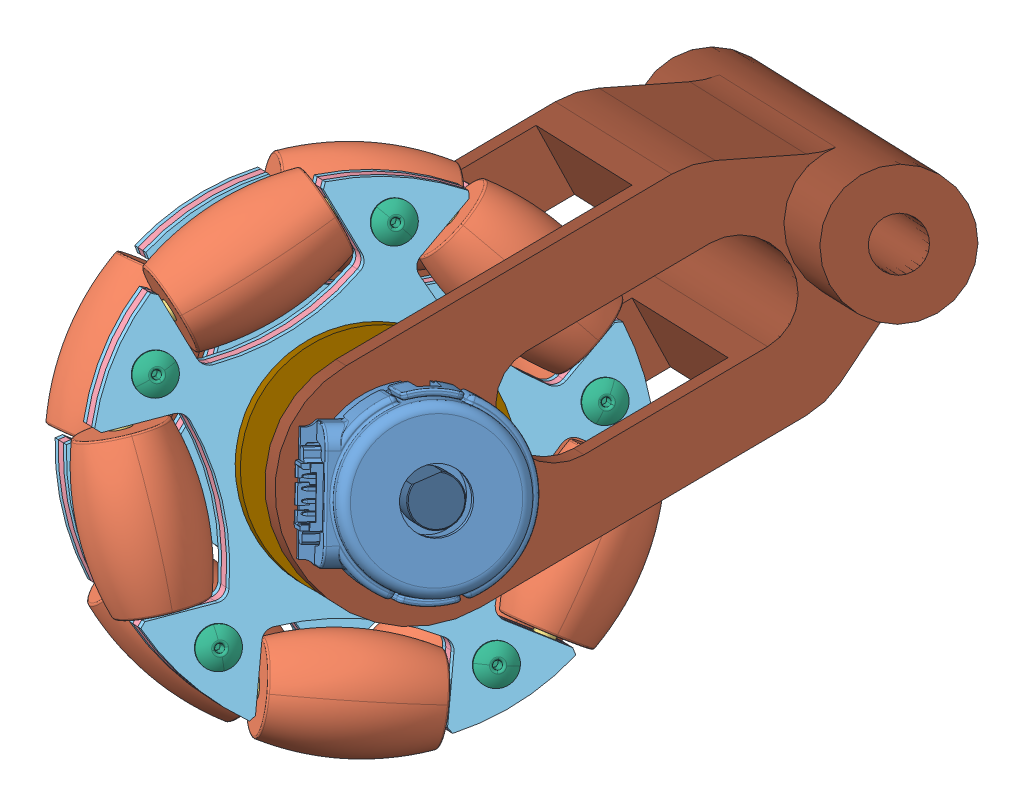
SolidWorks assembly odemetrywheel, configuration Default. Lengths in mm.
Overall size (110.18 106.44 131.13).
58 component instances, 11 part files, 18 mates.
Components (placement in the parent):
- Copy of E4T-X-236-S-H-M-X^odemetrywheel-1: Copy of E4T-X-236-S-H-M-X^odemetrywheel [Default] at (-122.0307 128.6085 91.9811) x (0.321002 -0.882221 0.344446) z (-0.571631 0.109496 0.813172) size (21.88 13.62 23.95) (virtual)
- (Nex) [RB-Nex-75] [14145] 60mm Aluminum Omni Wheel - SolidWorks Model.STEP-1: (Nex) [RB-Nex-75] [14145] 60mm Aluminum Omni Wheel - SolidWorks Model.STEP [Default] at (-143.5514 115.5576 78.6101) x (0.083964 -0.777278 0.62353) z (-0.755113 -0.457926 -0.469157) size (78.62 80.66 25.5)
  - 60mm90__5______-______________(A__ ).STEP-1: 60mm90__5______-______________(A__ ).STEP [Default] at (0 0 6.25) size (64.79 61.62 13)
    - 60mm90__5______-______________(A__).STEP-1: 60mm90__5______-______________(A__).STEP [Default] at origin size (25 13 13)
      - 60mm90__5______-______(A__).STEP-1: 60mm90__5______-______(A__).STEP [Default] at origin size (18.5 13 13)
      - 60mm90__5______-______-__(A__).STEP-1: 60mm90__5______-______-__(A__).STEP [Default] at (0 23.5 0) x (1 0 0) z (0 -0.978837 -0.204643) size (25 2.5 2.5)
    - 60mm90__5______-______________(A__).STEP-2: 60mm90__5______-______________(A__).STEP [Default] x (0.309017 -0.951057 0) z (0 0 1) size (25 13 13)
      - 60mm90__5______-______(A__).STEP-1: 60mm90__5______-______(A__).STEP [Default] at origin size (18.5 13 13)
      - 60mm90__5______-______-__(A__).STEP-1: 60mm90__5______-______-__(A__).STEP [Default] at (0 23.5 0) x (1 0 0) z (0 -0.978837 -0.204643) size (25 2.5 2.5)
    - 60mm90__5______-______________(A__).STEP-3: 60mm90__5______-______________(A__).STEP [Default] x (-0.809017 -0.587785 0) z (0 0 1) size (25 13 13)
      - 60mm90__5______-______(A__).STEP-1: 60mm90__5______-______(A__).STEP [Default] at origin size (18.5 13 13)
      - 60mm90__5______-______-__(A__).STEP-1: 60mm90__5______-______-__(A__).STEP [Default] at (0 23.5 0) x (1 0 0) z (0 -0.978837 -0.204643) size (25 2.5 2.5)
    - 60mm90__5______-______________(A__).STEP-4: 60mm90__5______-______________(A__).STEP [Default] x (-0.809017 0.587785 0) z (0 0 1) size (25 13 13)
      - 60mm90__5______-______(A__).STEP-1: 60mm90__5______-______(A__).STEP [Default] at origin size (18.5 13 13)
      - 60mm90__5______-______-__(A__).STEP-1: 60mm90__5______-______-__(A__).STEP [Default] at (0 23.5 0) x (1 0 0) z (0 -0.978837 -0.204643) size (25 2.5 2.5)
    - 60mm90__5______-______________(A__).STEP-5: 60mm90__5______-______________(A__).STEP [Default] x (0.309017 0.951057 0) z (0 0 1) size (25 13 13)
      - 60mm90__5______-______(A__).STEP-1: 60mm90__5______-______(A__).STEP [Default] at origin size (18.5 13 13)
      - 60mm90__5______-______-__(A__).STEP-1: 60mm90__5______-______-__(A__).STEP [Default] at (0 23.5 0) x (1 0 0) z (0 -0.978837 -0.204643) size (25 2.5 2.5)
    - 60mm90__5______-____________(A__).STEP-1: 60mm90__5______-____________(A__).STEP [Default] at origin size (56.91 55.07 2.5)
    - 60mm90__5______-__________(A__).STEP-1: 60mm90__5______-__________(A__).STEP [Default] at (0 0 2) size (56.91 55.07 1.5)
    - 60mm90__5______-__________(A__).STEP-2: 60mm90__5______-__________(A__).STEP [Default] at (0 0 -2) size (56.91 55.07 1.5)
    - ____3X5.STEP-1: ____3X5.STEP [Default] at (-14.1068 19.4164 -10.9942) x (1 0 0) z (0 -1 0) size (4.8 7.01 4.8)
    - ____3X5.STEP-2: ____3X5.STEP [Default] at (14.1068 19.4164 -10.9942) x (0.309017 -0.951057 0) z (-0.951057 -0.309017 0) size (4.8 7.01 4.8)
    - ____3X5.STEP-3: ____3X5.STEP [Default] at (22.8254 -7.4164 -10.9942) x (-0.809017 -0.587785 0) z (-0.587785 0.809017 0) size (4.8 7.01 4.8)
    - ____3X5.STEP-4: ____3X5.STEP [Default] at (0 -24 -10.9942) x (-0.809017 0.587785 0) z (0.587785 0.809017 0) size (4.8 7.01 4.8)
    - ____3X5.STEP-5: ____3X5.STEP [Default] at (-22.8254 -7.4164 -10.9942) x (0.309017 0.951057 0) z (0.951057 -0.309017 0) size (4.8 7.01 4.8)
  - 60mm90__5______-______________(A__ ).STEP-2: 60mm90__5______-______________(A__ ).STEP [Default] at (0 0 -6.25) x (0.309017 0.951057 0) z (0 0 -1) size (64.79 61.62 13)
    - 60mm90__5______-______________(A__).STEP-1: 60mm90__5______-______________(A__).STEP [Default] at origin size (25 13 13)
      - 60mm90__5______-______(A__).STEP-1: 60mm90__5______-______(A__).STEP [Default] at origin size (18.5 13 13)
      - 60mm90__5______-______-__(A__).STEP-1: 60mm90__5______-______-__(A__).STEP [Default] at (0 23.5 0) x (1 0 0) z (0 -0.978837 -0.204643) size (25 2.5 2.5)
    - 60mm90__5______-______________(A__).STEP-2: 60mm90__5______-______________(A__).STEP [Default] x (0.309017 -0.951057 0) z (0 0 1) size (25 13 13)
      - 60mm90__5______-______(A__).STEP-1: 60mm90__5______-______(A__).STEP [Default] at origin size (18.5 13 13)
      - 60mm90__5______-______-__(A__).STEP-1: 60mm90__5______-______-__(A__).STEP [Default] at (0 23.5 0) x (1 0 0) z (0 -0.978837 -0.204643) size (25 2.5 2.5)
    - 60mm90__5______-______________(A__).STEP-3: 60mm90__5______-______________(A__).STEP [Default] x (-0.809017 -0.587785 0) z (0 0 1) size (25 13 13)
      - 60mm90__5______-______(A__).STEP-1: 60mm90__5______-______(A__).STEP [Default] at origin size (18.5 13 13)
      - 60mm90__5______-______-__(A__).STEP-1: 60mm90__5______-______-__(A__).STEP [Default] at (0 23.5 0) x (1 0 0) z (0 -0.978837 -0.204643) size (25 2.5 2.5)
    - 60mm90__5______-______________(A__).STEP-4: 60mm90__5______-______________(A__).STEP [Default] x (-0.809017 0.587785 0) z (0 0 1) size (25 13 13)
      - 60mm90__5______-______(A__).STEP-1: 60mm90__5______-______(A__).STEP [Default] at origin size (18.5 13 13)
      - 60mm90__5______-______-__(A__).STEP-1: 60mm90__5______-______-__(A__).STEP [Default] at (0 23.5 0) x (1 0 0) z (0 -0.978837 -0.204643) size (25 2.5 2.5)
    - 60mm90__5______-______________(A__).STEP-5: 60mm90__5______-______________(A__).STEP [Default] x (0.309017 0.951057 0) z (0 0 1) size (25 13 13)
      - 60mm90__5______-______(A__).STEP-1: 60mm90__5______-______(A__).STEP [Default] at origin size (18.5 13 13)
      - 60mm90__5______-______-__(A__).STEP-1: 60mm90__5______-______-__(A__).STEP [Default] at (0 23.5 0) x (1 0 0) z (0 -0.978837 -0.204643) size (25 2.5 2.5)
    - 60mm90__5______-____________(A__).STEP-1: 60mm90__5______-____________(A__).STEP [Default] at origin size (56.91 55.07 2.5)
    - 60mm90__5______-__________(A__).STEP-1: 60mm90__5______-__________(A__).STEP [Default] at (0 0 2) size (56.91 55.07 1.5)
    - 60mm90__5______-__________(A__).STEP-2: 60mm90__5______-__________(A__).STEP [Default] at (0 0 -2) size (56.91 55.07 1.5)
    - ____3X5.STEP-1: ____3X5.STEP [Default] at (-14.1068 19.4164 -10.9942) x (1 0 0) z (0 -1 0) size (4.8 7.01 4.8)
    - ____3X5.STEP-2: ____3X5.STEP [Default] at (14.1068 19.4164 -10.9942) x (0.309017 -0.951057 0) z (-0.951057 -0.309017 0) size (4.8 7.01 4.8)
    - ____3X5.STEP-3: ____3X5.STEP [Default] at (22.8254 -7.4164 -10.9942) x (-0.809017 -0.587785 0) z (-0.587785 0.809017 0) size (4.8 7.01 4.8)
    - ____3X5.STEP-4: ____3X5.STEP [Default] at (0 -24 -10.9942) x (-0.809017 0.587785 0) z (0.587785 0.809017 0) size (4.8 7.01 4.8)
    - ____3X5.STEP-5: ____3X5.STEP [Default] at (-22.8254 -7.4164 -10.9942) x (0.309017 0.951057 0) z (0.951057 -0.309017 0) size (4.8 7.01 4.8)
  - 60mm90__5______-__________(A__)-0.STEP-1: 60mm90__5______-__________(A__)-0.STEP [Default] x (0.994522 0.104528 0) z (0 0 1) size (28 28 10)
  - __________(M3X20).STEP-1: __________(M3X20).STEP [Default] at (-1.0975 10.4425 7.5) x (0.905128 0.425139 0) z (0.425139 -0.905128 0) size (5.5 21 5.5)
  - __________(M3X20).STEP-2: __________(M3X20).STEP [Default] at (-8.4947 -6.1717 7.5) x (-0.820745 0.571294 0) z (0.571294 0.820745 0) size (5.5 21 5.5)
  - __________(M3X20).STEP-3: __________(M3X20).STEP [Default] at (9.5922 -4.2707 7.5) x (-0.084383 -0.996433 0) z (-0.996433 0.084383 0) size (5.5 21 5.5)
- omnihub-1: omnihub [Default] at (-137.8881 118.9921 82.1288) x (-0.01554 0.727922 -0.685484) z (0.65541 -0.510327 -0.556779) size (28 16 28)
- omnihub-2: omnihub [Default] at (-149.2148 112.1232 75.0915) x (-0.575372 0.805917 0.139443) z (-0.314247 -0.375235 0.872036) size (28 16 28)
- 80mm axle.step-1: 80mm axle.step [Default] at (-173.8855 97.162 59.7634) x (0.400386 0.244542 -0.883114) z (0.519129 -0.854695 -0.00131) size (6 80 5.5)
- omnipart3-1: omnipart3 [Default] at (-172.7473 94.5623 85.3467) x (-0.334546 -0.346284 0.876451) z (-0.563811 0.818774 0.108287) size (74 92.22 28)
Mates (geometry in assembly coordinates):
- Concentric1: concentric: cylinder of (Nex) [RB-Nex-75] [14145] 60mm Aluminum Omni Wheel - SolidWorks Model.STEP-1/60mm90__5______-__________(A__)-0.STEP-1 through (-156.0108 108.0019 70.869) axis (-0.755113 -0.457926 -0.469157) radius 6; cylinder of omnihub-1 through (-137.8881 118.9921 82.1288) axis (0.755113 0.457926 0.469157) radius 3.01
- Concentric2: concentric: cylinder of (Nex) [RB-Nex-75] [14145] 60mm Aluminum Omni Wheel - SolidWorks Model.STEP-1/60mm90__5______-______________(A__ ).STEP-2/60mm90__5______-____________(A__).STEP-1 through (-143.0755 113.9073 90.1123) axis (0.755113 0.457926 0.469157) radius 1.5; cylinder of omnihub-1 through (-147.2286 111.3887 87.5319) axis (0.755113 0.457926 0.469157) radius 1.6
- Coincident1: coincident: plane of (Nex) [RB-Nex-75] [14145] 60mm Aluminum Omni Wheel - SolidWorks Model.STEP-1/60mm90__5______-______________(A__ ).STEP-2/60mm90__5______-____________(A__).STEP-1 through (-137.8881 118.9921 82.1288) normal (0.755113 0.457926 0.469157); plane of omnihub-1 through (-137.8881 118.9921 82.1288) normal (-0.755113 -0.457926 -0.469157)
- Concentric3: concentric: cylinder of (Nex) [RB-Nex-75] [14145] 60mm Aluminum Omni Wheel - SolidWorks Model.STEP-1/60mm90__5______-__________(A__)-0.STEP-1 through (-156.0108 108.0019 70.869) axis (-0.755113 -0.457926 -0.469157) radius 6; cylinder of omnihub-2 through (-149.2148 112.1232 75.0915) axis (-0.755113 -0.457926 -0.469157) radius 3.01
- Concentric4: concentric: cylinder of ? through (-140.4452 107.9096 70.4182) axis (-0.755113 -0.457926 -0.469157) radius 1.5; cylinder of omnihub-2 through (-136.2921 110.4282 72.9985) axis (-0.755113 -0.457926 -0.469157) radius 1.6
- Coincident2: coincident: plane of ? through (-149.2148 112.1232 75.0915) normal (-0.755113 -0.457926 -0.469157); plane of omnihub-2 through (-149.2148 112.1232 75.0915) normal (0.755113 0.457926 0.469157)
- Concentric12: concentric: cylinder of omnihub-1 through (-137.8881 118.9921 82.1288) axis (0.755113 0.457926 0.469157) radius 3.01; cylinder of 80mm axle.step-1 through (-113.4765 133.7961 97.2959) axis (-0.755113 -0.457926 -0.469157) radius 3
- Parallel2: parallel: plane of (Nex) [RB-Nex-75] [14145] 60mm Aluminum Omni Wheel - SolidWorks Model.STEP-1/60mm90__5______-______________(A__ ).STEP-1/60mm90__5______-__________(A__).STEP-2 through (-162.2808 117.594 99.3074) normal (-0.519129 0.854695 0.00131); plane of 80mm axle.step-1 through (-114.7743 135.9328 97.2992) normal (-0.519129 0.854695 0.00131)
- Concentric13: concentric: cylinder of omnihub-2 through (-161.2966 104.7964 67.585) axis (0.755113 0.457926 0.469157) radius 7.5; cylinder of omnipart3-1 through (-118.7959 130.5702 93.9909) axis (-0.755113 -0.457926 -0.469157) radius 6
- Coincident3: coincident: plane of omnihub-2 through (-158.0618 106.7581 69.5948) normal (-0.755113 -0.457926 -0.469157); plane of omnipart3-1 through (-169.1523 104.5857 89.5655) normal (0.755113 0.457926 0.469157)
- Parallel3: parallel: plane of Copy of E4T-X-236-S-H-M-X^odemetrywheel-1; plane of omnipart3-1 through (-115.0464 115.1837 -7.8629) normal (0.483319 0.094669 -0.870311)
- Coincident5: coincident: plane of Copy of E4T-X-236-S-H-M-X^odemetrywheel-1; plane of omnipart3-1 through (-172.9279 102.2961 87.2197) normal (-0.755113 -0.457926 -0.469157)
- Concentric14: concentric: cylinder of 80mm axle.step-1 through (-113.4765 133.7961 97.2959) axis (-0.755113 -0.457926 -0.469157) radius 3; cylinder of omnipart3-1 through (-122.0307 128.6085 91.9811) axis (-0.755113 -0.457926 -0.469157) radius 3
- Concentric15: concentric: cylinder of Copy of E4T-X-236-S-H-M-X^odemetrywheel-1 through (-121.0909 129.1785 92.565) axis (0.755113 0.457926 0.469157) radius 2.9997; cylinder of 80mm axle.step-1 through (-113.4765 133.7961 97.2959) axis (-0.755113 -0.457926 -0.469157) radius 3
- Concentric16: concentric: circle of Copy of E4T-X-236-S-H-M-X^odemetrywheel-1; circle of omnipart3-1
- Coincident6: coincident: plane of Copy of E4T-X-236-S-H-M-X^odemetrywheel-1 through (-122.0307 128.6085 91.9811) normal (-0.755113 -0.457926 -0.469157); plane of omnipart3-1 through (-129.7059 120.664 112.0887) normal (0.755113 0.457926 0.469157)
- Coincident7: coincident: plane of omnihub-1 through (-125.8063 126.3189 89.6353) normal (0.755113 0.457926 0.469157); plane of omnipart3-1 through (-133.4815 118.3744 109.7429) normal (-0.755113 -0.457926 -0.469157)
- Coincident8: coincident: plane of Copy of E4T-X-236-S-H-M-X^odemetrywheel-1 through (-113.4765 133.7961 97.2959) normal (0.755113 0.457926 0.469157); plane of 80mm axle.step-1 through (-113.4765 133.7961 97.2959) normal (0.755113 0.457926 0.469157)
